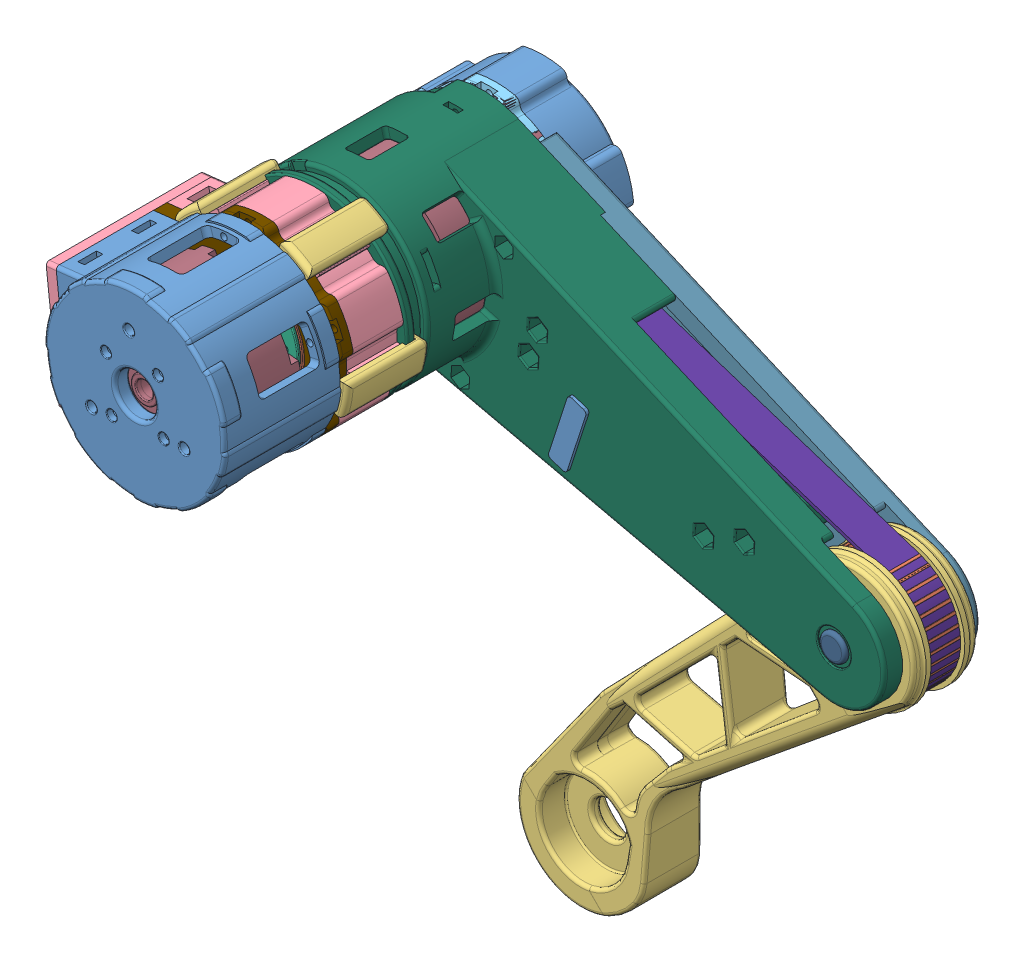
SolidWorks assembly Cycloid_Reducer, configuration 默认. Lengths in mm.
Overall size (206.27 233.62 123.37).
72 component instances, 42 part files, 154 mates.
Components (placement in the parent):
- 机壳-1: 机壳 [默认] at (0.0697 -3.5769 49.2366) size (53.7 51.8 15.06)
- 轴承20_27_4-1: 轴承20_27_4 [默认] at (0.0697 -3.5769 47.2366) x (-0.878044 -0.478581 0) z (0 0 1) size (32 32 4)
- M6x10销钉-1: M6x10销钉 [默认] at (16.2501 -15.3326 61.2366) x (-0.923728 -0.383049 0) z (0 0 -1) size (6 6 12)
- M6x10销钉-2: M6x10销钉 [默认] at (6.2501 -22.598 61.2366) x (-0.923728 -0.383049 0) z (0 0 -1) size (6 6 12)
- M6x10销钉-3: M6x10销钉 [默认] at (20.0697 -3.5769 61.2366) x (0.918679 0.395004 0) z (0 0 -1) size (6 6 12)
- M6x10销钉-4: M6x10销钉 [默认] at (16.2501 8.1788 61.2366) x (-0.923728 -0.383049 0) z (0 0 -1) size (6 6 12)
- M6x10销钉-5: M6x10销钉 [默认] at (-6.1106 -22.598 61.2366) x (-0.923728 -0.383049 0) z (0 0 -1) size (6 6 12)
- M6x10销钉-6: M6x10销钉 [默认] at (-19.9303 -3.5769 61.2366) x (-0.923728 -0.383049 0) z (0 0 -1) size (6 6 12)
- M6x10销钉-7: M6x10销钉 [默认] at (6.2501 15.4442 49.2366) x (0.445591 0.895237 0) z (0 0 1) size (6 6 12)
- M6x10销钉-8: M6x10销钉 [默认] at (-16.1106 -15.3326 61.2366) x (-0.923728 -0.383049 0) z (0 0 -1) size (6 6 12)
- M6x10销钉-9: M6x10销钉 [默认] at (-16.1106 8.1788 61.2366) x (-0.923728 -0.383049 0) z (0 0 -1) size (6 6 12)
- M6x10销钉-10: M6x10销钉 [默认] at (-6.1106 15.4442 61.2366) x (-0.923728 -0.383049 0) z (0 0 -1) size (6 6 12)
- Output_Shaft2-1: Output_Shaft2 [默认] at (0.0697 -3.5769 47.2366) x (-0.708861 0.705348 0) z (0.705348 0.708861 0) size (28 7.3 28)
- M2x18销钉-1: M2x18销钉 [默认] at (1.7635 7.2919 65.2366) x (-0.978807 0.204786 0) z (0 0 -1) size (2 2 18)
- M2x18销钉-2: M2x18销钉 [默认] at (10.93 -1.8291 65.2366) x (-0.483408 0.875395 0) z (0 0 -1) size (2 2 18)
- M2x18销钉-3: M2x18销钉 [默认] at (-9.7437 1.3926 65.2366) x (-0.398741 -0.917063 0) z (0 0 -1) size (2 2 18)
- M2x18销钉-4: M2x18销钉 [默认] at (5.088 -13.3655 65.2366) x (0.373454 0.927649 0) z (0 0 -1) size (2 2 18)
- M2x18销钉-5: M2x18销钉 [默认] at (-7.6891 -11.3744 65.2366) x (-0.923728 -0.383049 0) z (0 0 -1) size (2 2 18)
- 轴承20_27_4-2: 轴承20_27_4 [默认] at (0.0697 -3.5769 61.2366) x (0.939817 0.341678 0) z (0 0 1) size (32 32 4)
- 定位中间件-1: 定位中间件 [默认] at (0.0697 -3.5769 61.2366) x (-0.158888 0.987297 0) z (0.987297 0.158888 0) size (30 5 30)
- 轴承8_16_4-1: 轴承8_16_4 [默认] at (0.0697 -3.5769 65.2366) x (-0.472822 -0.881158 0) z (0.881158 -0.472822 0) size (16 4 16)
- 传动曲轴_2-2: 传动曲轴_2 [默认] at (-0.5979 -4.9201 53.2366) x (-0.288278 -0.957547 0) z (0 0 1) size (6 6 4)
- 轴承10_15_4-3: 轴承10_15_4 [默认] at (-0.5979 -4.9201 57.2366) x (0.992594 -0.121476 0) z (0 0 1) size (12 12 4)
- 摆线轮1-2: 摆线轮1 [默认] at (-0.5979 -4.9201 61.2366) x (-0.435447 0.900214 0) z (0 0 -1) size (35.87 36.36 4)
- 传动曲轴_2-3: 传动曲轴_2 [默认] at (-3.4705 -4.0553 49.2366) x (0.288278 0.957547 0) z (0 0 1) size (6 6 4)
- 摆线轮2-2: 摆线轮2 [默认] at (-3.4705 -4.0553 57.2366) x (0.293003 -0.956112 0) z (0 0 -1) size (35.87 36.36 4)
- 轴承10_15_4-4: 轴承10_15_4 [默认] at (-3.4705 -4.0553 53.2366) x (-0.104468 -0.994528 0) z (0 0 1) size (12 12 4)
- M1.5x14销轴-1: M1.5x14销轴 [默认] at (0.102 -2.2773 63.2366) x (1 0 0) z (0 1 0) size (1.5 14 1.5)
- M1.5x14销轴-2: M1.5x14销轴 [默认] at (-2.409 -5.7325 63.2366) x (1 0 0) z (0 1 0) size (1.5 14 1.5)
- 无刷电机-1: 无刷电机 [默认] at (0.0697 -3.5769 97.6366) x (0.024851 -0.999691 0) z (0.999691 0.024851 0) size (46 26.5 46)
- AS5600 Magntic encoder-1: AS5600 Magntic encoder [默认] at (0.0697 -3.5769 111.4366) x (0.891007 0.45399 0) z (0 0 -1) size (23.2 22.7 3.2)
- 电机架-2: 电机架 [默认] at (0.0697 -3.5769 75.2366) x (-0.45399 0.891007 0) z (0 0 1) size (136.75 136.75 49.55)
- 同步轮10mm-1: 同步轮10mm [GearTrax] at (0.0697 -3.5769 72.7366) x (0.158888 -0.987297 0) z (0 0 -1) size (38 38 13)
- 同步带-1: 同步带 [默认] at (0.0697 -3.5769 68.2366) x (0.951057 -0.309017 0) z (0 0 1) size (169.52 35.52 10)
- 外端盖-2: 外端盖 [默认] at (0.0697 -3.5769 130.2366) x (-0.869187 0.494484 0) z (0 0 1) size (59.92 54.36 4.17)
- 电机架 - 副本-1: 电机架 - 副本 [默认] at (0.0697 -3.5769 134.2366) x (0.993837 0.11085 0) z (0 0 1) size (53.85 54 34.57)
- 同步轮10mm - 副本 (2)-1: 同步轮10mm - 副本 (2) [GearTrax] at (127.5113 -44.9852 73.2366) x (-0.676631 0.736322 0) z (0 0 1) size (35.45 35.52 10)
- 狗腿子1_1-1: 狗腿子1_1 [GearTrax] at (127.5113 -44.9852 73.2366) x (0.676631 -0.736322 0) z (0 0 1) size (50.75 159.33 20.11)
- 机壳 - 副本-1: 机壳 - 副本 [默认] at (0.0697 -3.5769 118.2366) x (-0.869187 0.494484 0) z (0 0 1) size (59.92 55.56 20)
- 轴承20_27_4-3: 轴承20_27_4 [默认] at (0.0697 -3.5769 116.2366) x (0.99915 0.041225 0) z (0 0 1) size (32 32 4)
- 输出盘-1: 输出盘 [默认] at (0.0697 -3.5769 116.2366) x (-0.923728 -0.383049 0) z (-0.383049 0.923728 0) size (28 7.3 28)
- 轴承35-44-5-1: 轴承35-44-5 [默认] at (0.0697 -3.5769 114.7366) x (0.910683 -0.413105 0) z (0.413105 0.910683 0) size (44 5 44)
- 无刷电机-2: 无刷电机 [默认] at (0.0697 -3.5769 156.6366) x (-0.996994 -0.077476 0) z (0.077476 -0.996994 0) size (46 26.5 46)
- 轴承20_27_4-4: 轴承20_27_4 [默认] at (0.0697 -3.5769 130.2366) size (32 32 4)
- 定位中间件-2: 定位中间件 [默认] at (0.0697 -3.5769 130.2366) x (-0.923728 -0.383049 0) z (-0.383049 0.923728 0) size (30 5 30)
- 连轴1-1: 连轴1 [默认] at (0.0697 -3.5769 80.4366) x (0.999691 0.024851 0) z (-0.024851 0.999691 0) size (18 3 18)
- 轴承9-20-6-1: 轴承9-20-6 [默认] at (0.0697 -3.5769 69.2366) x (0.99926 -0.038453 0) z (-0.038453 -0.99926 0) size (20 6 20)
- 轴套5-7-4-1: 轴套5-7-4 [默认] at (127.5113 -44.9852 84.2366) x (0.651338 -0.758788 0) z (-0.758788 -0.651338 0) size (7 4 7)
- 轴套5-7-4-2: 轴套5-7-4 [默认] at (127.5113 -44.9852 63.7366) x (-0.419076 -0.907951 0) z (0.907951 -0.419076 0) size (7 4 7)
- 字母钉-1: 字母钉 [默认] at (127.5113 -44.9852 58.5366) x (1 0 0) z (0 -1 0) size (8 30.4 8)
- 轴承5-13-4-1: 轴承5-13-4 [默认] at (127.5113 -44.9852 67.9366) x (1 0 0) z (0 1 0) size (13 4 13)
- 轴承5-13-4-2: 轴承5-13-4 [默认] at (127.5113 -44.9852 82.5366) x (0.964472 0.264184 0) z (-0.264184 0.964472 0) size (13 4 13)
- 联轴件2-1: 联轴件2 [默认] at (0.0697 -3.5769 111.4366) x (0.891007 0.45399 0) z (0.45399 -0.891007 0) size (23 3 23)
- 外端盖_0-1: 外端盖_0 [默认] at (0.0697 -3.5769 61.2366) size (53.7 51.8 5.37) (hidden)
- 机壳-2: 机壳 [默认] at (-30.1208 -16.9453 143.238) x (0.185609 -0.38444 -0.904298) z (-0.900536 -0.434782 0) size (53.7 51.8 15.06) (hidden)
- 外端盖_0-2: 外端盖_0 [默认] at (-40.9272 -22.1627 143.238) x (-0.048441 0.100333 -0.993774) z (-0.900536 -0.434782 0) size (53.7 51.8 5.37) (hidden)
- 狗腿子盖-1: 狗腿子盖 [默认] at (0.0697 -3.5769 66.7366) x (0.45399 -0.891007 0) z (0 0 -1) size (121.6 121.6 7.09)
- 输入轴F-1: 输入轴F [默认] at (-0.5979 -4.9201 51.2366) x (0.895486 -0.44509 0) z (0 0 1) size (18 18 20.2)
- 连轴1-2: 连轴1 [默认] at (0.0697 -3.5769 139.4366) x (0.996457 -0.084105 0) z (0.084105 0.996457 0) size (18 3 18)
- 输入轴F2-1: 输入轴F2 [默认] at (1.0374 -4.723 119.4366) x (0.764072 0.645131 0) z (0 0 1) size (18 18 10)
- 链接双头螺母3-6-20-1: 链接双头螺母3-6-20 [默认] at (48.6558 -30.5648 64.2366) x (0.681068 0.73222 0) z (0 0 1) size (6 6 20)
- cross recessed ctsk head screws type b gb-1: cross recessed ctsk head screws type b gb [GB_CROSS_SCREWS_TYPE136 M3X7-C] at (48.6558 -30.5648 88.1366) x (0 0 -1) z (-0.892221 0.451599 0) size (7 5.36 5.36)
- cross recessed ctsk head screws type b gb-2: cross recessed ctsk head screws type b gb [GB_CROSS_SCREWS_TYPE136 M3X7-C] at (48.6558 -30.5648 60.8366) x (0 0 1) z (-0.997387 0.072237 0) size (7 5.36 5.36)
- 零件1^Cycloid_Reducer-1: 零件1^Cycloid_Reducer [默认] at (0.0697 -3.5769 59.7366) x (0.45399 -0.891007 0) z (0 0 -1) (virtual)
- 盖板-1: 盖板 [默认] at (49.2023 -28.8828 60.8366) x (-0.309017 -0.951057 0) z (0 0 -1) size (19.8 5.8 1)
- 盖板-2: 盖板 [默认] at (49.1072 -28.8519 89.1366) x (-0.309017 -0.951057 0) z (0 0 -1) size (19.8 5.8 1)
- 轴套6-8-15-1: 轴套6-8-15 [默认] at (48.6558 -30.5648 66.2366) x (0.483838 -0.875157 0) z (0 0 1) size (8 8 15)
- 卡口-1: 卡口 [默认] at (0.0697 -3.5769 125.138) x (-0.72589 -0.687811 0) z (0.687811 -0.72589 0) size (9.58 24.32 4.46)
- 卡口-2: 卡口 [默认] at (0.0697 -3.5769 125.1366) x (0.182972 0.983118 0) z (-0.983118 0.182972 0) size (9.58 24.32 4.46)
- 卡口-3: 卡口 [默认] at (0.0697 -3.5769 125.1366) x (-0.87846 0.477817 0) z (-0.477817 -0.87846 0) size (9.58 24.32 4.46)
- 连接板-1: 连接板 [默认] at (-26.8846 -5.4872 139.7366) x (0 0 1) z (-0.993837 -0.11085 0) size (47 36 3)
- 外端盖00-1: 外端盖00 [默认] at (0.0697 -3.5769 61.2366) size (53.7 51.8 4.17)
Mates (geometry in assembly coordinates):
- 重合1: coincident: plane of 机壳-1 through (0.0697 8.9231 47.2366) normal (0 0 1); plane of 轴承20_27_4-1 through (0.0697 -3.5769 47.2366) normal (0 0 -1)
- 同心1: concentric: cylinder of 机壳-1 through (0.0697 -3.5769 41.2366) axis (0 0 1) radius 16; cylinder of 轴承20_27_4-1 through (0.0697 -3.5769 51.2366) axis (0 0 -1) radius 12.5
- 重合2: coincident: plane of 机壳-1 through (0.0697 -3.5769 49.2366) normal (0 0 1); plane of M6x10销钉-1 through (16.2501 -15.3326 49.2366) normal (0 0 -1)
- 同心2: concentric: cylinder of 机壳-1 through (16.2501 -15.3326 49.2366) axis (0 0 1) radius 3; cylinder of M6x10销钉-1 through (16.2501 -15.3326 49.2366) axis (0 0 1) radius 3
- 重合3: coincident: plane of 机壳-1 through (0.0697 -3.5769 49.2366) normal (0 0 1); plane of M6x10销钉-2 through (6.2501 -22.598 49.2366) normal (0 0 -1)
- 同心3: concentric: cylinder of 机壳-1 through (6.2501 -22.598 49.2366) axis (0 0 1) radius 3; cylinder of M6x10销钉-2 through (6.2501 -22.598 49.2366) axis (0 0 1) radius 3
- 重合4: coincident: plane of M6x10销钉-3 through (20.0697 -3.5769 49.2366) normal (0 0 -1); plane of 机壳-1 through (0.0697 -3.5769 49.2366) normal (0 0 1)
- 同心4: concentric: cylinder of 机壳-1 through (20.0697 -3.5769 49.2366) axis (0 0 1) radius 3; cylinder of M6x10销钉-3 through (20.0697 -3.5769 49.2366) axis (0 0 1) radius 3
- 重合5: coincident: plane of 机壳-1 through (0.0697 -3.5769 49.2366) normal (0 0 1); plane of M6x10销钉-4 through (16.2501 8.1788 49.2366) normal (0 0 -1)
- 同心5: concentric: cylinder of 机壳-1 through (16.2501 8.1788 49.2366) axis (0 0 1) radius 3; cylinder of M6x10销钉-4 through (16.2501 8.1788 49.2366) axis (0 0 1) radius 3
- 同心6: concentric: cylinder of 机壳-1 through (6.2501 15.4442 49.2366) axis (0 0 1) radius 3; cylinder of M6x10销钉-7 through (6.2501 15.4442 61.2366) axis (0 0 -1) radius 3
- 重合6: coincident: plane of 机壳-1 through (0.0697 -3.5769 49.2366) normal (0 0 1); plane of M6x10销钉-7 through (6.2501 15.4442 49.2366) normal (0 0 -1)
- 重合7: coincident: plane of 机壳-1 through (0.0697 -3.5769 49.2366) normal (0 0 1); plane of M6x10销钉-5 through (-6.1106 -22.598 49.2366) normal (0 0 -1)
- 同心7: concentric: cylinder of 机壳-1 through (-6.1106 -22.598 49.2366) axis (0 0 1) radius 3; cylinder of M6x10销钉-5 through (-6.1106 -22.598 49.2366) axis (0 0 1) radius 3
- 重合8: coincident: plane of 机壳-1 through (0.0697 -3.5769 49.2366) normal (0 0 1); plane of M6x10销钉-8 through (-16.1106 -15.3326 49.2366) normal (0 0 -1)
- 同心9: concentric: cylinder of 机壳-1 through (-16.1106 -15.3326 49.2366) axis (0 0 1) radius 3; cylinder of M6x10销钉-8 through (-16.1106 -15.3326 49.2366) axis (0 0 1) radius 3
- 重合9: coincident: plane of 机壳-1 through (0.0697 -3.5769 49.2366) normal (0 0 1); plane of M6x10销钉-6 through (-19.9303 -3.5769 49.2366) normal (0 0 -1)
- 同心10: concentric: cylinder of 机壳-1 through (-19.9303 -3.5769 49.2366) axis (0 0 1) radius 3; cylinder of M6x10销钉-6 through (-19.9303 -3.5769 49.2366) axis (0 0 1) radius 3
- 重合10: coincident: circle of 机壳-1; plane of M6x10销钉-9 through (-16.1106 8.1788 49.2366) normal (0 0 -1)
- 同心11: concentric: cylinder of 机壳-1 through (-16.1106 8.1788 49.2366) axis (0 0 1) radius 3; cylinder of M6x10销钉-9 through (-16.1106 8.1788 49.2366) axis (0 0 1) radius 3
- 重合11: coincident: plane of 机壳-1 through (0.0697 -3.5769 49.2366) normal (0 0 1); plane of M6x10销钉-10 through (-6.1106 15.4442 49.2366) normal (0 0 -1)
- 同心12: concentric: cylinder of 机壳-1 through (-6.1106 15.4442 49.2366) axis (0 0 1) radius 3; cylinder of M6x10销钉-10 through (-6.1106 15.4442 49.2366) axis (0 0 1) radius 3
- 同心13: concentric: cylinder of 轴承20_27_4-1 through (0.0697 -3.5769 51.2366) axis (0 0 -1) radius 12.5; cylinder of Output_Shaft2-1 through (0.0697 -3.5769 52.7366) axis (0 0 -1) radius 12.5
- 重合12: coincident: plane of 轴承20_27_4-1 through (0.0697 -3.5769 47.2366) normal (0 0 -1); plane of Output_Shaft2-1 through (0.0697 -3.5769 47.2366) normal (0 0 1)
- 重合13: coincident: plane of Output_Shaft2-1 through (0.0697 -3.5769 47.2366) normal (0 0 1); plane of M2x18销钉-1 through (1.7635 7.2919 47.2366) normal (0 0 -1)
- 同心14: concentric: cylinder of Output_Shaft2-1 through (1.7635 7.2919 52.7366) axis (0 0 -1) radius 1; cylinder of M2x18销钉-1 through (1.7635 7.2919 47.2366) axis (0 0 1) radius 1
- 重合14: coincident: plane of Output_Shaft2-1 through (0.0697 -3.5769 47.2366) normal (0 0 1); plane of M2x18销钉-2 through (10.93 -1.8291 47.2366) normal (0 0 -1)
- 同心15: concentric: cylinder of Output_Shaft2-1 through (10.93 -1.8291 52.7366) axis (0 0 -1) radius 1; cylinder of M2x18销钉-2 through (10.93 -1.8291 47.2366) axis (0 0 1) radius 1
- 重合15: coincident: plane of Output_Shaft2-1 through (0.0697 -3.5769 47.2366) normal (0 0 1); plane of M2x18销钉-3 through (-9.7437 1.3926 47.2366) normal (0 0 -1)
- 同心16: concentric: cylinder of Output_Shaft2-1 through (-9.7437 1.3926 52.7366) axis (0 0 -1) radius 1; cylinder of M2x18销钉-3 through (-9.7437 1.3926 47.2366) axis (0 0 1) radius 1
- 重合16: coincident: plane of Output_Shaft2-1 through (0.0697 -3.5769 47.2366) normal (0 0 1); plane of M2x18销钉-5 through (-7.6891 -11.3744 47.2366) normal (0 0 -1)
- 同心17: concentric: cylinder of Output_Shaft2-1 through (-7.6891 -11.3744 52.7366) axis (0 0 -1) radius 1; cylinder of M2x18销钉-5 through (-7.6891 -11.3744 47.2366) axis (0 0 1) radius 1
- 重合17: coincident: plane of Output_Shaft2-1 through (0.0697 -3.5769 47.2366) normal (0 0 1); plane of M2x18销钉-4 through (5.088 -13.3655 47.2366) normal (0 0 -1)
- 同心18: concentric: cylinder of Output_Shaft2-1 through (5.088 -13.3655 52.7366) axis (0 0 -1) radius 1; cylinder of M2x18销钉-4 through (5.088 -13.3655 47.2366) axis (0 0 1) radius 1
- 同心22: concentric: cylinder of M2x18销钉-2 through (10.93 -1.8291 47.2366) axis (0 0 1) radius 1; cylinder of 定位中间件-1 through (10.93 -1.8291 64.2366) axis (0 0 -1) radius 1
- 同心23: concentric: cylinder of M2x18销钉-3 through (-9.7437 1.3926 47.2366) axis (0 0 1) radius 1; cylinder of 定位中间件-1 through (-9.7437 1.3926 64.2366) axis (0 0 -1) radius 1
- 同心24: concentric: cylinder of 轴承20_27_4-2 through (0.0697 -3.5769 65.2366) axis (0 0 -1) radius 12.5; cylinder of 定位中间件-1 through (0.0697 -3.5769 65.2366) axis (0 0 -1) radius 12.5
- 同心25: concentric: cylinder of 轴承20_27_4-2 through (0.0697 -3.5769 65.2366) axis (0 0 -1) radius 12.5; cylinder of 定位中间件-1 through (0.0697 -3.5769 65.2366) axis (0 0 -1) radius 12.5
- 重合20: coincident: plane of 轴承20_27_4-2 through (0.0697 -3.5769 65.2366) normal (0 0 1); plane of 定位中间件-1 through (0.0697 -3.5769 65.2366) normal (0 0 -1)
- 同心26: concentric: cylinder of 定位中间件-1 through (0.0697 -3.5769 65.2366) axis (0 0 -1) radius 8; cylinder of 轴承8_16_4-1 through (0.0697 -3.5769 61.2366) axis (0 0 1) radius 8
- 重合25: coincident: plane of 定位中间件-1 through (0.0697 -3.5769 61.2366) normal (0 0 -1); plane of 轴承8_16_4-1 through (0.0697 -3.5769 61.2366) normal (0 0 -1)
- 同心46: concentric: cylinder of 传动曲轴_2-2 through (-0.5979 -4.9201 57.2366) axis (0 0 -1) radius 3; cylinder of 轴承10_15_4-3 through (-0.5979 -4.9201 61.2366) axis (0 0 -1) radius 3
- 重合38: coincident: plane of 轴承8_16_4-1 through (0.0697 -3.5769 61.2366) normal (0 0 -1); plane of 摆线轮1-2 through (14.9748 2.6293 61.2366) normal (0 0 1)
- 同心47: concentric: cylinder of 轴承10_15_4-3 through (-0.5979 -4.9201 61.2366) axis (0 0 -1) radius 6; cylinder of 摆线轮1-2 through (-0.5979 -4.9201 57.2366) axis (0 0 1) radius 6
- 同心48: concentric: cylinder of 传动曲轴_2-2 through (-1.6595 -3.2429 57.2366) axis (0 0 -1) radius 0.8; cylinder of 传动曲轴_2-3 through (-1.6595 -3.2429 53.2366) axis (0 0 -1) radius 0.8
- 同心49: concentric: cylinder of 传动曲轴_2-2 through (-2.409 -5.7325 57.2366) axis (0 0 -1) radius 0.8; cylinder of 传动曲轴_2-3 through (-2.409 -5.7325 53.2366) axis (0 0 -1) radius 0.8
- 重合39: coincident: plane of 传动曲轴_2-2 through (-0.5979 -4.9201 53.2366) normal (0 0 -1); circle of 传动曲轴_2-3
- 同心50: concentric: cylinder of 传动曲轴_2-3 through (-3.4705 -4.0553 53.2366) axis (0 0 -1) radius 3; cylinder of 轴承10_15_4-4 through (-3.4705 -4.0553 57.2366) axis (0 0 -1) radius 3
- 重合40: coincident: plane of 轴承10_15_4-3 through (-0.5979 -4.9201 57.2366) normal (0 0 -1); plane of 轴承10_15_4-4 through (-3.4705 -4.0553 57.2366) normal (0 0 1)
- 同心52: concentric: cylinder of 摆线轮2-2 through (-3.4705 -4.0553 53.2366) axis (0 0 1) radius 6; cylinder of 轴承10_15_4-4 through (-3.4705 -4.0553 57.2366) axis (0 0 -1) radius 6
- 重合42: coincident: plane of 轴承10_15_4-3 through (-0.5979 -4.9201 57.2366) normal (0 0 -1); plane of 摆线轮2-2 through (-20.0128 -9.1404 57.2366) normal (0 0 1)
- 同心53: concentric: cylinder of 传动曲轴_2-3 through (-2.409 -5.7325 53.2366) axis (0 0 -1) radius 0.8; cylinder of M1.5x14销轴-2 through (-2.409 -5.7325 49.2366) axis (0 0 1) radius 0.75
- 重合43: coincident: plane of 传动曲轴_2-3 through (-3.4705 -4.0553 49.2366) normal (0 0 -1); plane of M1.5x14销轴-2 through (-2.409 -5.7325 49.2366) normal (0 0 -1)
- 重合44: coincident: plane of 传动曲轴_2-3 through (-3.4705 -4.0553 49.2366) normal (0 0 -1); plane of M1.5x14销轴-1 through (0.102 -2.2773 49.2366) normal (0 0 -1)
- 同心62: concentric: cylinder of 机壳-1 through (0.0697 -3.5769 39.2366) axis (0 0 1) radius 24.5; cylinder of 无刷电机-1 through (0.0697 -3.5769 96.6366) axis (0 0 1) radius 23
- 同心63: concentric: cylinder of 机壳-1 through (0.0697 -3.5769 39.2366) axis (0 0 1) radius 24.5; cylinder of 电机架-2 through (0.0697 -3.5769 79.2366) axis (0 0 -1) radius 27
- 同心75: concentric: cylinder of Output_Shaft2-1 through (0.0697 -3.5769 45.4356) axis (0 0 1) radius 2; cylinder of 同步带-1 through (0.0697 -3.5769 78.2366) axis (0 0 -1) radius 16.76
- 重合73: coincident: plane of 外端盖-2 through (0.0697 -3.5769 134.2366) normal (0 0 1); plane of 电机架 - 副本-1 through (-3.8208 8.3022 134.2366) normal (0 0 -1)
- 同心79: concentric: cylinder of AS5600 Magntic encoder-1 through (-10.3919 -0.1777 111.4366) axis (0 0 -1) radius 1.5; cylinder of 电机架-2 through (-10.3919 -0.1777 75.2356) axis (0 0 1) radius 1.4
- 同心80: concentric: cylinder of AS5600 Magntic encoder-1 through (3.4689 6.8847 111.4366) axis (0 0 -1) radius 1.5; cylinder of 电机架-2 through (3.4689 6.8847 75.2356) axis (0 0 1) radius 1.4
- 同心81: concentric: cylinder of 机壳-1 through (0.0697 -3.5769 39.2366) axis (0 0 1) radius 24.5; cylinder of 同步轮10mm-1 through (0.0697 -3.5769 110.3493) axis (0 0 -1) radius 10
- 重合79: coincident: plane of 同步轮10mm - 副本 (2)-1 through (153.494 -45.1798 68.2366) normal (0 0 -1); plane of 狗腿子1_1-1 through (127.5113 -44.9852 68.2366) normal (0 0 1)
- 重合80: coincident: plane of 电机架-2 through (127.5113 -44.9852 82.7366) normal (0 0 -1); plane of 狗腿子1_1-1 through (127.5113 -44.9852 82.7366) normal (0 0 1)
- 同心85: concentric: cylinder of 同步带-1 through (127.5113 -44.9852 78.2366) axis (0 0 -1) radius 16.76; cylinder of 同步轮10mm - 副本 (2)-1 through (127.5113 -44.9852 78.2366) axis (0 0 -1) radius 3
- 重合81: coincident: plane of 同步带-1 through (0.0697 -3.5769 78.2366) normal (0 0 1); plane of 狗腿子1_1-1 through (127.5113 -44.9852 78.2366) normal (0 0 -1)
- 同心95: concentric: cylinder of 电机架-2 through (0.0697 -3.5769 79.2366) axis (0 0 -1) radius 27; cylinder of 机壳 - 副本-1 through (0.0697 -3.5769 108.2366) axis (0 0 1) radius 24.5
- 重合89: coincident: plane of 外端盖-2 through (0.0697 -3.5769 130.2366) normal (0 0 -1); plane of 机壳 - 副本-1 through (0.0697 -3.5769 130.2366) normal (0 0 1)
- 同心98: concentric: cylinder of 机壳 - 副本-1 through (0.0697 -3.5769 110.2366) axis (0 0 1) radius 16; cylinder of 轴承20_27_4-3 through (0.0697 -3.5769 120.2366) axis (0 0 -1) radius 16
- 重合91: coincident: plane of 机壳 - 副本-1 through (-6.1113 -14.4417 116.2366) normal (0 0 1); plane of 轴承20_27_4-3 through (0.0697 -3.5769 116.2366) normal (0 0 -1)
- 同心99: concentric: cylinder of 轴承20_27_4-3 through (0.0697 -3.5769 120.2366) axis (0 0 -1) radius 12.5; cylinder of 输出盘-1 through (0.0697 -3.5769 121.7366) axis (0 0 -1) radius 12.5
- 重合92: coincident: plane of 轴承20_27_4-3 through (0.0697 -3.5769 116.2366) normal (0 0 -1); plane of 输出盘-1 through (0.0697 -3.5769 116.2366) normal (0 0 1)
- 同心100: concentric: cylinder of 电机架-2 through (0.0697 -3.5769 114.7366) axis (0 0 -1) radius 22; cylinder of 轴承35-44-5-1 through (0.0697 -3.5769 109.7366) axis (0 0 1) radius 22
- 重合93: coincident: plane of 电机架-2 through (0.0697 -3.5769 109.7366) normal (0 0 1); plane of 轴承35-44-5-1 through (0.0697 -3.5769 109.7366) normal (0 0 -1)
- 重合94: coincident: plane of 机壳 - 副本-1 through (0.0697 -3.5769 114.7366) normal (0 0 -1); plane of 轴承35-44-5-1 through (0.0697 -3.5769 114.7366) normal (0 0 1)
- 同心101: concentric: cylinder of 电机架 - 副本-1 through (0.0697 -3.5769 231.6117) axis (0 0 -1) radius 23.75; cylinder of 无刷电机-2 through (0.0697 -3.5769 155.6366) axis (0 0 1) radius 23
- 重合95: coincident: plane of 电机架 - 副本-1 through (0.0697 -3.5769 164.4366) normal (0 0 -1); plane of 无刷电机-2 through (11.7867 10.8129 164.4366) normal (0 0 1)
- 同心102: concentric: cylinder of 外端盖-2 through (0.0697 -3.5769 134.2366) axis (0 0 -1) radius 16; cylinder of 轴承20_27_4-4 through (0.0697 -3.5769 134.2366) axis (0 0 -1) radius 16
- 重合96: coincident: plane of 外端盖-2 through (0.0697 -3.5769 134.2366) normal (0 0 1); plane of 轴承20_27_4-4 through (0.0697 -3.5769 134.2366) normal (0 0 1)
- 同心103: concentric: cylinder of 轴承20_27_4-4 through (0.0697 -3.5769 134.2366) axis (0 0 -1) radius 12.5; cylinder of 定位中间件-2 through (0.0697 -3.5769 134.2366) axis (0 0 -1) radius 12.5
- 重合97: coincident: plane of 轴承20_27_4-4 through (0.0697 -3.5769 134.2366) normal (0 0 1); plane of 定位中间件-2 through (0.0697 -3.5769 134.2366) normal (0 0 -1)
- 同心104: concentric: cylinder of 无刷电机-1 through (0.0697 -3.5769 80.4366) axis (0 0 -1) radius 2.5; cylinder of 连轴1-1 through (0.0697 -3.5769 77.4366) axis (0 0 1) radius 9
- 重合98: coincident: plane of 无刷电机-1 through (-0.5018 19.416 80.4366) normal (0 0 -1); plane of 连轴1-1 through (0.0697 -3.5769 80.4366) normal (0 0 1)
- 同心110: concentric: cylinder of 电机架-2 through (127.5113 -44.9852 65.2366) axis (0 0 1) radius 3.5; cylinder of 轴套5-7-4-1 through (127.5113 -44.9852 88.2366) axis (0 0 -1) radius 3.5
- 重合103: coincident: plane of 电机架-2 through (127.5113 -44.9852 88.2366) normal (0 0 1); plane of 轴套5-7-4-1 through (127.5113 -44.9852 88.2366) normal (0 0 1)
- 同心111: concentric: cylinder of 电机架-2 through (127.5113 -44.9852 65.2366) axis (0 0 1) radius 3.5; cylinder of 同步轮10mm - 副本 (2)-1 through (127.5113 -44.9852 78.2366) axis (0 0 -1) radius 3
- 同心114: concentric: cylinder of 轴套5-7-4-2 through (127.5113 -44.9852 59.7366) axis (0 0 1) radius 2.5; cylinder of 字母钉-1 through (127.5113 -44.9852 87.7366) axis (0 0 -1) radius 2.5
- 同心115: concentric: cylinder of 同步轮10mm - 副本 (2)-1 through (119.3917 -36.1493 78.2366) axis (0 0 -1) radius 1; cylinder of 狗腿子1_1-1 through (119.3917 -36.1493 63.1963) axis (0 0 1) radius 1
- 同心116: concentric: cylinder of 同步轮10mm - 副本 (2)-1 through (135.6309 -53.821 78.2366) axis (0 0 -1) radius 1; cylinder of 狗腿子1_1-1 through (135.6309 -53.821 63.1963) axis (0 0 1) radius 1
- 同心117: concentric: cylinder of 同步轮10mm - 副本 (2)-1 through (127.5113 -44.9852 78.2366) axis (0 0 -1) radius 3; cylinder of 字母钉-1 through (127.5113 -44.9852 87.7366) axis (0 0 -1) radius 2.5
- 重合106: coincident: plane of 狗腿子1_1-1 through (127.5113 -44.9852 67.9366) normal (0 0 -1); plane of 轴承5-13-4-1 through (127.5113 -44.9852 67.9366) normal (0 0 1)
- 同心119: concentric: cylinder of 字母钉-1 through (127.5113 -44.9852 87.7366) axis (0 0 -1) radius 2.5; cylinder of 轴承5-13-4-1 through (127.5113 -44.9852 63.9366) axis (0 0 1) radius 2.5
- 同心120: concentric: cylinder of 狗腿子1_1-1 through (127.5113 -44.9852 60.1518) axis (0 0 1) radius 6.5; cylinder of 轴承5-13-4-2 through (127.5113 -44.9852 78.5366) axis (0 0 1) radius 6.5
- 重合107: coincident: plane of 狗腿子1_1-1 through (127.5113 -44.9852 78.5366) normal (0 0 1); plane of 轴承5-13-4-2 through (127.5113 -44.9852 78.5366) normal (0 0 -1)
- 同心121: concentric: cylinder of 外端盖-2 through (16.9158 -22.0488 140.2366) axis (0 0 -1) radius 1; cylinder of 机壳 - 副本-1 through (16.9158 -22.0488 113.4082) axis (0 0 1) radius 1
- 重合108: coincident: plane of AS5600 Magntic encoder-1 through (0.0697 -3.5769 111.4366) normal (0 0 1); plane of 联轴件2-1 through (-3.6449 -15.0094 111.4366) normal (0 0 -1)
- 同心122: concentric: cylinder of AS5600 Magntic encoder-1 through (-10.3919 -0.1777 111.4366) axis (0 0 -1) radius 1.5; cylinder of 联轴件2-1 through (-10.3919 -0.1777 114.4366) axis (0 0 -1) radius 1.475
- 同心123: concentric: cylinder of AS5600 Magntic encoder-1 through (-3.3294 -14.0385 111.4366) axis (0 0 -1) radius 1.5; cylinder of 联轴件2-1 through (-3.3294 -14.0385 112.9366) axis (0 0 1) radius 2.75
- 同心124: concentric: cylinder of 电机架 - 副本-1 through (0.0697 -3.5769 59.1772) axis (0 0 1) radius 26.5375; cylinder of 机壳 - 副本-1 through (0.0697 -3.5769 108.2366) axis (0 0 1) radius 24.5
- 同心125: concentric: cylinder of 外端盖-2 through (-12.2924 -25.3066 140.2366) axis (0 0 -1) radius 1; cylinder of 电机架 - 副本-1 through (-12.2924 -25.3066 148.1943) axis (0 0 -1) radius 0.975
- 同心126: concentric: cylinder of 机壳-1 through (0.0697 -3.5769 39.2366) axis (0 0 1) radius 24.5; cylinder of 外端盖_0-1 through (0.0697 -3.5769 53.1666) axis (0 0 1) radius 24.5
- 重合109: coincident: plane of 机壳-1 through (0.0697 -3.5769 61.2366) normal (0 0 1); plane of 外端盖_0-1 through (0.0697 -3.5769 61.2366) normal (0 0 -1)
- 同心127: concentric: cylinder of 机壳-1 through (23.8462 4.1485 44.4082) axis (0 0 1) radius 1; cylinder of 外端盖_0-1 through (23.8462 4.1485 71.2366) axis (0 0 -1) radius 1
- 重合110: coincident: plane of 电机架-2 through (0.0697 -3.5769 65.2366) normal (0 0 -1); plane of 外端盖_0-1 through (0.0697 -3.5769 65.2366) normal (0 0 1)
- 重合111: coincident: plane of 输出盘-1 through (0.0697 -3.5769 114.4366) normal (0 0 -1); plane of 联轴件2-1 through (-3.6449 -15.0094 114.4366) normal (0 0 1)
- 同心132: concentric: cylinder of 机壳-2 through (-21.1155 -12.5975 143.238) axis (-0.900536 -0.434782 0) radius 24.5; cylinder of 外端盖_0-2 through (-33.6599 -18.654 143.238) axis (-0.900536 -0.434782 0) radius 24.5
- 重合115: coincident: plane of 机壳-2 through (-40.9272 -22.1627 143.238) normal (-0.900536 -0.434782 0); plane of 外端盖_0-2 through (-40.9272 -22.1627 143.238) normal (0.900536 0.434782 0)
- 重合117: coincident: plane of 电机架-2 through (0.0697 -3.5769 66.7366) normal (0 0 -1); plane of 狗腿子盖-1 through (127.5113 -44.9852 66.7366) normal (0 0 1)
- 同心136: concentric: cylinder of 轴套5-7-4-2 through (127.5113 -44.9852 59.7366) axis (0 0 1) radius 3.5; cylinder of 狗腿子盖-1 through (127.5113 -44.9852 66.7366) axis (0 0 -1) radius 3.5
- 重合118: coincident: plane of 轴承8_16_4-1 through (0.0697 -3.5769 65.2366) normal (0 0 1); plane of 输入轴F-1 through (0.0697 -3.5769 65.2366) normal (0 0 -1)
- 同心137: concentric: cylinder of 轴承8_16_4-1 through (0.0697 -3.5769 61.2366) axis (0 0 1) radius 4; cylinder of 输入轴F-1 through (0.0697 -3.5769 45.6802) axis (0 0 1) radius 4
- 同心138: concentric: cylinder of 轴承9-20-6-1 through (0.0697 -3.5769 75.2366) axis (0 0 -1) radius 4.5; cylinder of 输入轴F-1 through (0.0697 -3.5769 77.4366) axis (0 0 -1) radius 4.5
- 重合119: coincident: plane of 轴承9-20-6-1 through (0.0697 -3.5769 69.2366) normal (0 0 -1); plane of 输入轴F-1 through (0.0697 -3.5769 69.2366) normal (0 0 1)
- 重合120: coincident: plane of 无刷电机-1 through (-13.6829 8.8818 105.4366) normal (0 0 1); plane of 电机架-2 through (0.0697 -3.5769 105.4366) normal (0 0 -1)
- 同心139: concentric: cylinder of 定位中间件-2 through (0.0697 -3.5769 134.2366) axis (0 0 -1) radius 8; cylinder of 输入轴F2-1 through (0.0697 -3.5769 113.8802) axis (0 0 1) radius 4
- 重合121: coincident: plane of 定位中间件-2 through (0.0697 -3.5769 133.4366) normal (0 0 1); plane of 输入轴F2-1 through (0.0697 -3.5769 133.4366) normal (0 0 -1)
- 同心140: concentric: cylinder of 无刷电机-2 through (0.0697 -3.5769 139.4366) axis (0 0 -1) radius 2.5; cylinder of 连轴1-2 through (0.0697 -3.5769 136.4366) axis (0 0 1) radius 9
- 重合122: coincident: plane of 无刷电机-2 through (23.0006 -1.795 139.4366) normal (0 0 -1); plane of 连轴1-2 through (0.0697 -3.5769 139.4366) normal (0 0 1)
- 同心142: concentric: cylinder of 无刷电机-1 through (-0.0794 2.4213 80.4366) axis (0 0 -1) radius 1.25; cylinder of 连轴1-1 through (-0.0794 2.4213 77.4366) axis (0 0 1) radius 1.475
- 同心144: concentric: cylinder of 机壳-1 through (0.0697 -3.5769 39.2366) axis (0 0 1) radius 24.5; cylinder of 狗腿子盖-1 through (0.0697 -3.5769 62.2366) axis (0 0 1) radius 27
- 同心145: concentric: cylinder of 机壳-1 through (0.0697 21.4231 44.4082) axis (0 0 1) radius 1; cylinder of 电机架-2 through (0.0697 21.4231 78.2366) axis (0 0 -1) radius 0.99
- 重合123: coincident: plane of 电机架-2 through (0.0697 -3.5769 84.2366) normal (0 0 -1); plane of 链接双头螺母3-6-20-1 through (48.6558 -30.5648 84.2366) normal (0 0 1)
- 相切1: tangent: plane of 电机架-2 through (55.1148 -20.3944 84.2366) normal (-0.951057 0.309017 0); cylinder of 链接双头螺母3-6-20-1 through (48.6558 -30.5648 84.2366) axis (0 0 -1) radius 3
- 同心150: concentric: cylinder of 链接双头螺母3-6-20-1 through (48.6558 -30.5648 64.2366) axis (0 0 1) radius 1.5; cylinder of cross recessed ctsk head screws type b gb-1 through (48.6558 -30.5648 81.1366) axis (0 0 1) radius 1.5
- 重合124: coincident: plane of 电机架-2 through (0.0697 -3.5769 86.7366) normal (0 0 1); circle of cross recessed ctsk head screws type b gb-1
- 同心151: concentric: cylinder of 链接双头螺母3-6-20-1 through (48.6558 -30.5648 64.2366) axis (0 0 1) radius 1.5; cylinder of cross recessed ctsk head screws type b gb-2 through (48.6558 -30.5648 67.8366) axis (0 0 -1) radius 1.5
- 重合125: coincident: plane of 狗腿子盖-1 through (0.0697 -3.5769 62.2366) normal (0 0 -1); circle of cross recessed ctsk head screws type b gb-2
- 在位1: in place: plane of 狗腿子盖-1 through (0.0697 -3.5769 59.7366) normal (0 0 -1); plane of ? through (0 0 59.7366) normal (0 0 -1); moOrthogonalPlaneRef_w of 狗腿子盖-1 through (0.0697 -3.5769 59.7366) normal (0 0 -1); plane of ? through (0 0 59.7366) normal (0 1 0); plane of 狗腿子盖-1 through (0.0697 -3.5769 59.7366) normal (0 0 -1); plane of ? through (0 0 59.7366) normal (-1 0 0); plane of 狗腿子盖-1 through (0.0697 -3.5769 59.7366) normal (0 0 -1); unknown of 零件1^Cycloid_Reducer-1
- 重合126: coincident: plane of 狗腿子盖-1; plane of 零件1^Cycloid_Reducer-1
- 重合127: coincident: moOrthogonalPlaneRef_w of 狗腿子盖-1 through (0.0697 -3.5769 59.7366) normal (-0.891007 -0.45399 0); plane of 零件1^Cycloid_Reducer-1 through (0.0697 -3.5769 59.7366) normal (-0.891007 -0.45399 0)
- 重合128: coincident: moOrthogonalPlaneRef_w of 狗腿子盖-1 through (0.0697 -3.5769 59.7366) normal (-0.45399 0.891007 0); plane of 零件1^Cycloid_Reducer-1 through (0.0697 -3.5769 59.7366) normal (0.45399 -0.891007 0)
- 重合129: coincident: plane of cross recessed ctsk head screws type b gb-2 through (48.6558 -30.5648 60.8366) normal (0 0 -1); plane of 盖板-1 through (50.1691 -19.8775 60.8366) normal (0 0 1)
- 重合130: coincident: plane of 狗腿子盖-1 through (53.6882 -19.9308 54.7366) normal (-0.309017 -0.951057 0); plane of 盖板-1 through (54.0337 -20.0431 59.8366) normal (0.309017 0.951057 0)
- 重合131: coincident: plane of 狗腿子盖-1 through (55.0197 -20.3635 62.2366) normal (-0.951057 0.309017 0); plane of 盖板-1 through (49.2215 -38.2084 59.8366) normal (0.951057 -0.309017 0)
- 重合132: coincident: plane of cross recessed ctsk head screws type b gb-1 through (48.6558 -30.5648 88.1366) normal (0 0 1); plane of 盖板-2 through (50.074 -19.8466 88.1366) normal (0 0 -1)
- 重合133: coincident: plane of 电机架-2 through (48.7805 -39.242 86.7366) normal (-0.951057 0.309017 0); plane of 盖板-2 through (49.1264 -38.1775 88.1366) normal (0.951057 -0.309017 0)
- 重合134: coincident: plane of 电机架-2 through (47.9819 -18.0767 81.2366) normal (-0.309017 -0.951057 0); plane of 盖板-2 through (53.9386 -20.0122 88.1366) normal (0.309017 0.951057 0)
- 重合135: coincident: plane of 电机架-2 through (47.3638 -19.9789 81.2366) normal (0 0 -1); plane of 轴套6-8-15-1 through (48.6558 -30.5648 81.2366) normal (0 0 1)
- 同心152: concentric: cylinder of 链接双头螺母3-6-20-1 through (48.6558 -30.5648 84.2366) axis (0 0 -1) radius 3; cylinder of 轴套6-8-15-1 through (48.6558 -30.5648 81.2366) axis (0 0 -1) radius 4
- 同心153: concentric: cylinder of 机壳 - 副本-1 through (0.0697 -3.5769 140.421) axis (0 0 -1) radius 26; cylinder of 卡口-1 through (0.0697 -3.5769 115.138) axis (0 0 -1) radius 27
- 同心154: concentric: cylinder of 机壳 - 副本-1 through (0.0697 -3.5769 140.421) axis (0 0 -1) radius 26; cylinder of 卡口-3 through (0.0697 -3.5769 110.1366) axis (0 0 1) radius 29
- 重合136: coincident: plane of 电机架 - 副本-1 through (-3.8208 8.3022 134.2366) normal (0 0 -1); plane of 卡口-3 through (0.0697 -3.5769 134.2366) normal (0 0 1)
- 同心155: concentric: cylinder of 机壳 - 副本-1 through (0.0697 -3.5769 140.421) axis (0 0 -1) radius 26; cylinder of 卡口-2 through (0.0697 -3.5769 110.1366) axis (0 0 1) radius 29
- 重合137: coincident: plane of 电机架 - 副本-1 through (-3.8208 8.3022 134.2366) normal (0 0 -1); plane of 卡口-2 through (0.0697 -3.5769 134.2366) normal (0 0 1)
- 重合141: coincident: plane of 机壳 - 副本-1 through (-31.4082 35.0694 130.2366) normal (-0.993837 -0.11085 0); plane of 连接板-1 through (-25.0002 -22.3825 117.2366) normal (0.993837 0.11085 0)
- 重合142: coincident: plane of 机壳 - 副本-1 through (0.0697 -3.5769 116.2366) normal (0 0 -1); plane of 连接板-1 through (-27.9817 -22.715 116.2366) normal (0 0 -1)
- 重合144: coincident: line of 机壳 - 副本-1 through (-28.8799 12.4018 130.2366) axis (0 0 -1); line of 连接板-1 through (-28.8799 12.4018 162.2366) axis (0 0 -1)
- 同心156: concentric: cylinder of 定位中间件-1 through (10.1062 -8.6594 63.2366) axis (0 0 1) radius 0.74; cylinder of 同步轮10mm-1 through (10.1062 -8.6594 75.2366) axis (0 0 -1) radius 0.75
- 同心157: concentric: cylinder of 机壳-1 through (0.0697 -3.5769 39.2366) axis (0 0 1) radius 24.5; cylinder of 外端盖00-1 through (0.0697 -3.5769 65.2366) axis (0 0 -1) radius 16
- 重合146: coincident: plane of 机壳-1 through (0.0697 -3.5769 61.2366) normal (0 0 1); plane of 外端盖00-1 through (0.0697 -3.5769 61.2366) normal (0 0 -1)
- 同心158: concentric: cylinder of 机壳-1 through (0.0697 21.4231 44.4082) axis (0 0 1) radius 1; cylinder of 外端盖00-1 through (0.0697 21.4231 71.2366) axis (0 0 -1) radius 1
- 重合147: coincident: plane of 定位中间件-1 through (0.0697 -3.5769 61.2366) normal (0 0 -1); plane of 轴承10_15_4-3 through (-0.5979 -4.9201 61.2366) normal (0 0 1)
- 重合148: coincident: plane of 轴承20_27_4-2 through (0.0697 -3.5769 65.2366) normal (0 0 1); plane of 外端盖00-1 through (0.0697 -3.5769 65.2366) normal (0 0 1)
- 重合149: coincident: plane of 定位中间件-1 through (0.0697 -3.5769 66.2366) normal (0 0 1); plane of 同步轮10mm-1 through (0.0697 -3.5769 66.2366) normal (0 0 -1)
- 重合150: coincident: circle of 传动曲轴_2-2; circle of 输入轴F-1
